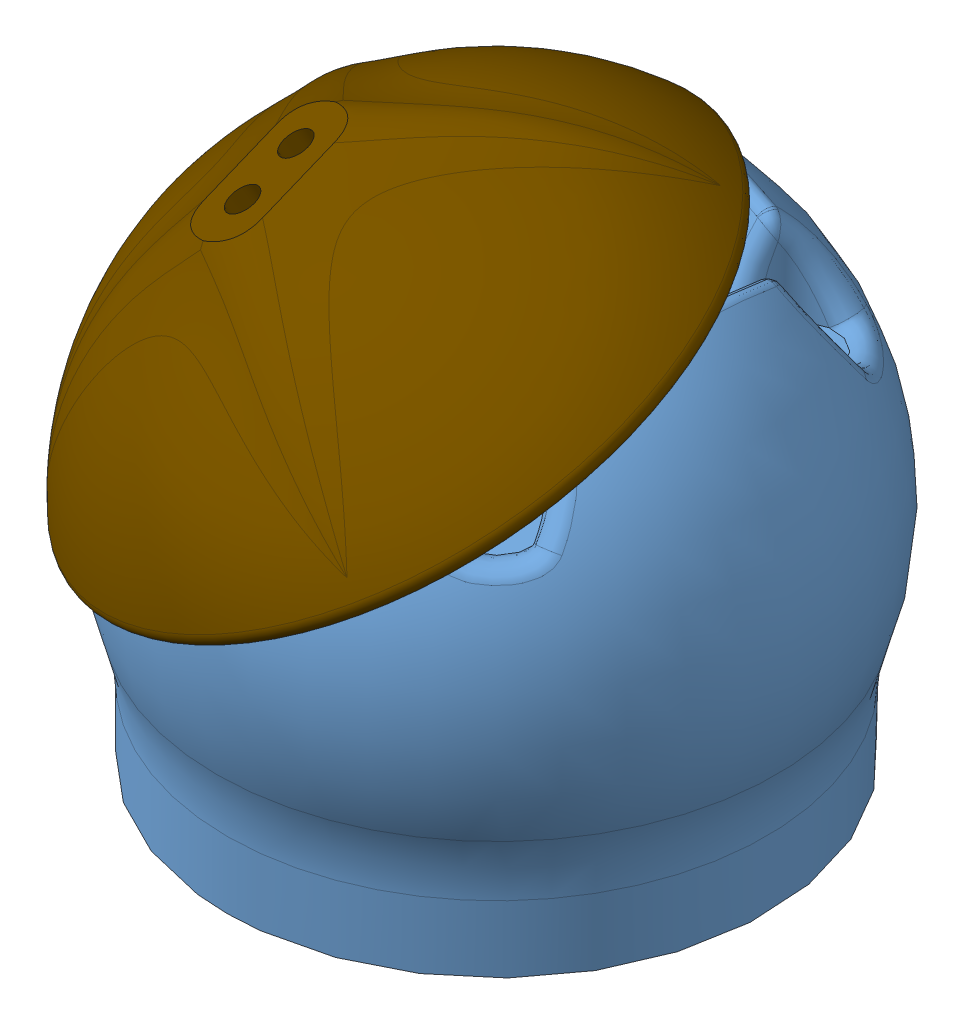
SolidWorks assembly base, configuration По умолчанию. Lengths in mm.
Overall size (188.08 196.84 198.3).
76 component instances, 18 part files, 8 mates.
Components (placement in the parent):
- gimbal_housing_gimbal01-1: gimbal_housing_gimbal01 [По умолчанию] at origin size (165.53 128.62 165.53)
- rings-1: rings [По умолчанию] at (0 48 0) x (-1 0 0) z (0 0 -1) size (129.11 101.62 135) (flexible)
  - gimbal_outer_ring_bottom_gimbal05-1: gimbal_outer_ring_bottom_gimbal05 [По умолчанию] at origin size (115 15 135)
  - gimbal_inner_ring_bottom_gimbal07-2: gimbal_inner_ring_bottom_gimbal07 [По умолчанию] at (0.05 1.1138 5.6721) x (0 0.378137 0.92575) z (-1 0 0) size (80 15 64)
  - M6x40mm-3: M6x40mm [По умолчанию] at (61.65 15 0) x (0 1 0) z (0 0 1) size (11.6 44.3 11.6)
  - M6 reinforced washer-1: M6 reinforced washer [По умолчанию] at (23.05 15 0) x (0 0 1) z (-1 0 0) size (17.7 17.7 1.4)
  - 8x6x18mm hub-1: 8x6x18mm hub [По умолчанию] at (33.45 15 0) x (0 0 -1) z (1 0 0) size (8 8 17.9)
  - M6 reinforced washer-2: M6 reinforced washer [По умолчанию] at (32.05 15 0) x (0 0 -1) z (1 0 0) size (17.7 17.7 1.4)
  - 608_bearing_v1-1: 608_bearing_v1 [По умолчанию] at (40.4 15 0) x (0 1 0) z (0 0 1) size (22 7.15 22)
  - 608_bearing_v1-2: 608_bearing_v1 [По умолчанию] at (47.35 15 0) x (0 1 0) z (0 0 1) size (22 7.15 22)
  - M8 washer_regular-1: M8 washer_regular [По умолчанию] at (48.95 15 0) x (0 0 1) z (-1 0 0) size (15.8 15.8 1.5)
  - M8 washer_regular-2: M8 washer_regular [По умолчанию] at (50.45 15 0) x (0 0 1) z (-1 0 0) size (15.8 15.8 1.5)
  - M8 washer_regular-3: M8 washer_regular [По умолчанию] at (51.95 15 0) x (0 0 1) z (-1 0 0) size (15.8 15.8 1.5)
  - M6 nut-1: M6 nut [По умолчанию] at (51.95 15 0) x (0 0 -1) z (1 0 0) size (10.85 9.54 4.7)
  - 608_bearing_v1-4: 608_bearing_v1 [По умолчанию] at (-33.45 15 0) x (0 1 0) z (0 0 1) size (22 7.15 22)
  - 608_bearing_v1-5: 608_bearing_v1 [По умолчанию] at (-47.35 15 0) x (0 -0.829409 0.558642) z (0 0.558642 0.829409) size (22 7.15 22)
  - M6 reinforced washer-3: M6 reinforced washer [По умолчанию] at (-21.55 15 0) x (0 0 1) z (-1 0 0) size (17.7 17.7 1.4)
  - M6 reinforced washer-4: M6 reinforced washer [По умолчанию] at (-31.95 15 0) x (0 0 1) z (-1 0 0) size (17.7 17.7 1.4)
  - M6x40mm-4: M6x40mm [По умолчанию] at (-61.55 15 0) x (0 -1 0) z (0 0 1) size (11.6 44.3 11.6)
  - 8x6x18mm hub-2: 8x6x18mm hub [По умолчанию] at (-33.35 15 0) x (0 0 1) z (-1 0 0) size (8 8 17.9)
  - M6 nut-2: M6 nut [По умолчанию] at (-51.95 15 0) x (0 0 1) z (-1 0 0) size (10.85 9.54 4.7)
  - M8 washer_regular-4: M8 washer_regular [По умолчанию] at (-48.95 15 0) x (0 0 -1) z (1 0 0) size (15.8 15.8 1.5)
  - M8 washer_regular-5: M8 washer_regular [По умолчанию] at (-51.95 15 0) x (0 0 -1) z (1 0 0) size (15.8 15.8 1.5)
  - M8 washer_regular-6: M8 washer_regular [По умолчанию] at (-50.45 15 0) x (0 0 -1) z (1 0 0) size (15.8 15.8 1.5)
  - lever_connector-1: lever_connector [По умолчанию] at (10.9946 42.8564 -11.3243) x (-0.939693 0.316625 -0.12933) z (0 0.378137 0.92575) size (26.14 78.07 91.4)
    - gimbal_stick_connector_p1_gimbal08-1: gimbal_stick_connector_p1_gimbal08 [По умолчанию] at origin size (25 40 38)
    - 608_bearing_v1-1: 608_bearing_v1 [По умолчанию] at (0 32 27.35) x (0.977584 0.210544 0) z (-0.210544 0.977584 0) size (22 7.15 22)
    - 608_bearing_v1-2: 608_bearing_v1 [По умолчанию] at (0 32 -20.5) x (0.979079 0.203481 0) z (-0.203481 0.979079 0) size (22 7.15 22)
    - gimbal_stick_connector_p2_gimbal09-1: gimbal_stick_connector_p2_gimbal09 [По умолчанию] at (0 45 0) x (-1 0 0) z (0 0 1) size (25 7.8 38)
    - bolt_M8_55mm-1: bolt_M8_55mm [По умолчанию] at (0 22 8) x (0.5 0 -0.866025) z (0.866025 0 0.5) size (15.95 60 12.56)
    - 608_bearing_v1-3: 608_bearing_v1 [По умолчанию] at (0 32 34.3) x (1 0 0) z (0 1 0) size (22 7.15 22)
    - 608_bearing_v1-4: 608_bearing_v1 [По умолчанию] at (0 32 -27.45) x (0.986358 -0.164615 0) z (0.164615 0.986358 0) size (22 7.15 22)
    - bolt_M8_55mm-3: bolt_M8_55mm [По умолчанию] at (0 22 -8) size (15.95 60 12.56)
    - M6x80mm-1: M6x80mm [По умолчанию] at (0 32 -41.1) x (0.829335 0.558752 0) z (0.558752 -0.829335 0) size (11.6 84.3 11.6)
    - 8x6x18mm hub-1: 8x6x18mm hub [По умолчанию] at (0 32 20.4) x (0.798366 0.602173 0) z (0 0 1) size (8 8 17.9)
    - 8x6x18mm hub-2: 8x6x18mm hub [По умолчанию] at (0 32 -37.4) size (8 8 17.9)
    - M8 washer_regular-2: M8 washer_regular [По умолчанию] at (0 32 34.4) size (15.8 15.8 1.5)
    - M8 washer_regular-3: M8 washer_regular [По умолчанию] at (0 32 35.9) size (15.8 15.8 1.5)
    - M8 washer_regular-5: M8 washer_regular [По умолчанию] at (0 32 -36) size (15.8 15.8 1.5)
    - M8 washer_regular-6: M8 washer_regular [По умолчанию] at (0 32 -37.5) size (15.8 15.8 1.5)
    - M6 nut-1: M6 nut [По умолчанию] at (0 32 -42.2) size (10.85 9.54 4.7)
    - 6x6x4mm_square-1: 6x6x4mm_square [По умолчанию] at (0 29 -45.2) x (0 0 1) z (-1 0 0) size (6 6 4)
    - M6 reinforced washer-1: M6 reinforced washer [По умолчанию] at (0 32 19) size (17.7 17.7 1.4)
    - M8 washer_regular-7: M8 washer_regular [По умолчанию] at (0 32 37.4) size (15.8 15.8 1.5)
    - M6 reinforced washer-2: M6 reinforced washer [По умолчанию] at (0 32 -20.4) size (17.7 17.7 1.4)
  - gimbal_outer_ring_top_gimbal04-1: gimbal_outer_ring_top_gimbal04 [По умолчанию] at (0 30 0) x (1 0 0) z (0 0 -1) size (125 15 135)
  - M6 nut-3: M6 nut [По умолчанию] at (56.65 15 0) x (0 0 -1) z (1 0 0) size (10.85 9.54 4.7)
  - 6x6x4mm_square-1: 6x6x4mm_square [По умолчанию] at (64.35 12.0002 -0.0307) x (-1 0 0) z (0 0.010219 -0.999948) size (6 6 4)
  - gimbal_inner_ring_top_gimbal06-1: gimbal_inner_ring_top_gimbal06 [По умолчанию] at (0.05 28.8862 -5.6721) x (0 0.378137 0.92575) z (1 0 0) size (88 15 64)
  - M4x40mm-1: M4x40mm [По умолчанию] at (37.6298 -10 -17.5) size (7.7 43 7.7)
  - M4x40mm-2: M4x40mm [По умолчанию] at (37.6298 -10 17.5) x (0.68152 0 -0.7318) z (0.7318 0 0.68152) size (7.7 43 7.7)
  - M4x40mm-3: M4x40mm [По умолчанию] at (20 -10 51.2348) size (7.7 43 7.7)
  - M4x40mm-4: M4x40mm [По умолчанию] at (0 -10 55) size (7.7 43 7.7)
  - M4x40mm-5: M4x40mm [По умолчанию] at (-20 -10 51.2348) size (7.7 43 7.7)
  - M4x40mm-6: M4x40mm [По умолчанию] at (-37.6298 -10 17.5) x (-0.731527 0 0.681812) z (-0.681812 0 -0.731527) size (7.7 43 7.7)
  - M4x40mm-7: M4x40mm [По умолчанию] at (-37.6298 -10 -17.5) x (0.922857 0 0.385142) z (-0.385142 0 0.922857) size (7.7 43 7.7)
  - M4x40mm-8: M4x40mm [По умолчанию] at (27.05 -11.547 1.1217) x (-0.165378 -0.37293 -0.913002) z (0.98623 -0.062536 -0.153099) size (7.7 43 7.7)
  - M4x40mm-9: M4x40mm [По умолчанию] at (0 -10 -58.5) size (7.7 43 7.7)
  - M4x40mm-10: M4x40mm [По умолчанию] at (20 -10 -51.2348) x (0.96962 0 -0.244618) z (0.244618 0 0.96962) size (7.7 43 7.7)
  - M4x40mm-11: M4x40mm [По умолчанию] at (-20 -10 -51.2348) x (0.927234 0 0.374481) z (-0.374481 0 0.927234) size (7.7 43 7.7)
  - M4x40mm-12: M4x40mm [По умолчанию] at (16.55 1.1206 32.1343) x (-0.795453 0.229157 0.561019) z (-0.606015 -0.30079 -0.73639) size (7.7 43 7.7)
  - M4x40mm-13: M4x40mm [По умолчанию] at (-26.95 -11.547 1.1217) x (-0.319745 -0.358286 -0.877151) z (0.947503 -0.120908 -0.296004) size (7.7 43 7.7)
  - M4x40mm-14: M4x40mm [По умолчанию] at (16.55 4.3348 40.0032) x (1 0 0) z (0 0.378137 0.92575) size (7.7 43 7.7)
  - M4x40mm-15: M4x40mm [По умолчанию] at (27.05 -4.7405 17.7852) x (0.983978 -0.067418 -0.165052) z (0.17829 0.372078 0.910917) size (7.7 43 7.7)
  - M4x40mm-16: M4x40mm [По умолчанию] at (-16.45 1.1206 32.1343) x (0.962873 -0.10208 -0.249911) z (0.269955 0.364098 0.891379) size (7.7 43 7.7)
  - M4x40mm-17: M4x40mm [По умолчанию] at (-16.45 -20.6223 -21.0963) x (0.512517 -0.324697 -0.79492) z (0.858677 0.193801 0.474462) size (7.7 43 7.7)
  - M4x40mm-18: M4x40mm [По умолчанию] at (16.55 -20.6223 -21.0963) x (1 0 0) z (0 0.378137 0.92575) size (7.7 43 7.7)
  - M4x40mm-19: M4x40mm [По умолчанию] at (-16.45 -17.4081 -13.2274) x (0.790609 -0.231541 -0.566857) z (0.612322 0.298958 0.731906) size (7.7 43 7.7)
  - M4x40mm-20: M4x40mm [По умолчанию] at (-26.95 -4.7405 17.7852) x (1 0 0) z (0 0.378137 0.92575) size (7.7 43 7.7)
  - M4x40mm-21: M4x40mm [По умолчанию] at (16.55 -17.4081 -13.2274) x (-0.238156 -0.367257 -0.899113) z (0.971227 -0.090055 -0.220473) size (7.7 43 7.7)
  - M4x40mm-22: M4x40mm [По умолчанию] at (-16.45 4.3348 40.0032) x (1 0 0) z (0 0.378137 0.92575) size (7.7 43 7.7)
  - M4x40mm-23: M4x40mm [По умолчанию] at (-46 -10 17.5) size (7.7 43 7.7)
  - M4x40mm-24: M4x40mm [По умолчанию] at (46 -10 17.5) size (7.7 43 7.7)
  - M4x40mm-25: M4x40mm [По умолчанию] at (-46 -10 -17.5) size (7.7 43 7.7)
  - M4x40mm-26: M4x40mm [По умолчанию] at (46 -10 -17.5) size (7.7 43 7.7)
- friction_semi_sphere-1: friction_semi_sphere [Default] at (-12.2309 94.0006 12.6087) x (0 0.378137 -0.92575) z (0.939693 0.316625 0.12933) size (157.97 55.14 157.97)
Mates (geometry in assembly coordinates):
- Coincident1: coincident anti-aligned: plane of gimbal_housing_gimbal01-1 through (0 78 0) normal (0 -1 0); plane of rings-1/gimbal_outer_ring_top_gimbal04-1 through (0 78 0) normal (0 1 0)
- Concentric3: concentric anti-aligned: cylinder of gimbal_housing_gimbal01-1 through (-42.0729 0 42.0729) axis (0 1 0) radius 4.1; cylinder of rings-1/gimbal_outer_ring_bottom_gimbal05-1 through (-42.0729 63.5429 42.0729) axis (0 -1 0) radius 4.1
- Concentric4: concentric anti-aligned: cylinder of gimbal_housing_gimbal01-1 through (-42.0729 0 -42.0729) axis (0 1 0) radius 4.1; cylinder of rings-1/gimbal_outer_ring_bottom_gimbal05-1 through (-42.0729 63.5429 -42.0729) axis (0 -1 0) radius 4.1
- Angle2: planar angle = 0.349066 rad anti-aligned: plane of rings-1/lever_connector-1/gimbal_stick_connector_p1_gimbal08-1 through (14.4323 67.202 -18.8616) normal (0.939693 0.316625 0.12933); plane of gimbal_housing_gimbal01-1 through (30 0 -30) normal (-1 0 0)
- Concentric22: concentric aligned: cylinder of rings-1/lever_connector-1/bolt_M8_55mm-1 through (-22.2813 122.5888 15.6443) axis (0.34202 -0.86992 -0.355332) radius 3.825; cylinder of friction_semi_sphere-1 through (-31.0895 144.9922 24.7953) axis (0.34202 -0.86992 -0.355332) radius 4.15
- Concentric24: concentric aligned: cylinder of rings-1/lever_connector-1/bolt_M8_55mm-3 through (-22.2813 116.5386 30.4563) axis (0.34202 -0.86992 -0.355332) radius 3.825; cylinder of friction_semi_sphere-1 through (-31.0895 138.942 39.6073) axis (0.34202 -0.86992 -0.355332) radius 4.15
- Concentric25: concentric: sphere of gimbal_housing_gimbal01-1; sphere of friction_semi_sphere-1
- Distance1: distance = 0.2 mm aligned: sphere of friction_semi_sphere-1; sphere of gimbal_housing_gimbal01-1
